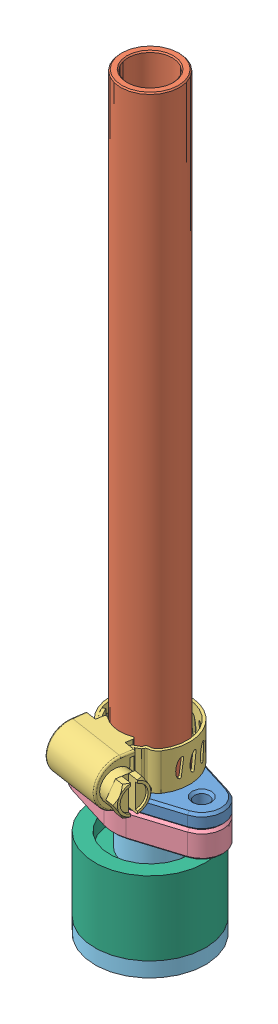
SolidWorks assembly AARL_QR_FR_TE, configuration Default. Lengths in mm.
Overall size (31.5 161.13 30.58).
6 component instances, 6 part files, 11 mates.
Components (placement in the parent):
- AARL_QR_FR_TE_001-1: AARL_QR_FR_TE_001 [Default] at origin size (31.5 15.88 15.88)
- AARL_QR_PN_PA_FL_SH_FL_001-1: AARL_QR_PN_PA_FL_SH_FL_001 [Resting] at (0 68.2625 0) size (12.7 130.18 12.7)
- AARL_Puppy_18_02_57_011-5388K140_Hose-Clamp-1: AARL_Puppy_18_02_57_011-5388K140_Hose-Clamp [5388K14] at (0 8.128 0) x (0.988722 0 0.149764) z (0 -1 0) size (19.43 23.71 9.91)
- AARL_QR_FR_TE_002-1: AARL_QR_FR_TE_002 [Default] x (1 0 0) z (0 -1 0) size (31.5 15.88 5.56)
- AARL_QR_FR_TE_003-1: AARL_QR_FR_TE_003 [Default] at (0 -27.7812 0) x (0.982152 0 0.18809) z (-0.18809 0 0.982152) size (23.81 22.23 23.81)
- AARL_QR_FR_TE_004-1: AARL_QR_FR_TE_004 [Default] at (0 -24.6062 0) x (-0.999983 0 0.005769) z (0 -1 0) size (23.81 23.81 15.88)
Mates (geometry in assembly coordinates):
- Concentric1: concentric anti-aligned: cylinder of AARL_QR_FR_TE_001-1 through (0 0 0) axis (0 -1 0) radius 4.3656; cylinder of AARL_QR_PN_PA_FL_SH_FL_001-1 through (0 79.8711 0) axis (0 1 0) radius 6.35
- Coincident1: coincident anti-aligned: plane of AARL_QR_FR_TE_001-1 through (7.9375 3.175 0) normal (0 1 0); plane of AARL_QR_PN_PA_FL_SH_FL_001-1 through (6.35 3.175 0) normal (0 -1 0)
- Concentric2: concentric aligned: cylinder of AARL_QR_PN_PA_FL_SH_FL_001-1 through (0 79.8711 0) axis (0 1 0) radius 6.35; cylinder of AARL_Puppy_18_02_57_011-5388K140_Hose-Clamp-1 through (0 3.175 0) axis (0 1 0) radius 6.5507
- Coincident2: coincident anti-aligned: plane of AARL_QR_FR_TE_001-1 through (7.9375 3.175 0) normal (0 1 0); plane of AARL_Puppy_18_02_57_011-5388K140_Hose-Clamp-1 through (0 3.175 0) normal (0 -1 0)
- Concentric6: concentric anti-aligned: cylinder of AARL_QR_FR_TE_001-1 through (-11.1125 23.3998 0) axis (0 -1 0) radius 1.5875; cylinder of AARL_QR_FR_TE_002-1 through (-11.1125 -5.5563 0) axis (0 1 0) radius 1.5875
- Concentric7: concentric anti-aligned: cylinder of AARL_QR_FR_TE_001-1 through (11.1125 23.3998 0) axis (0 -1 0) radius 1.5875; cylinder of AARL_QR_FR_TE_002-1 through (11.1125 -5.5563 0) axis (0 1 0) radius 1.5875
- Coincident5: coincident anti-aligned: plane of AARL_QR_FR_TE_001-1 through (0 0 0) normal (0 -1 0); plane of AARL_QR_FR_TE_002-1 through (-11.1125 0 0) normal (0 1 0)
- Concentric8: concentric aligned: cylinder of AARL_QR_FR_TE_002-1 through (0 -5.5563 0) axis (0 1 0) radius 1.5875; cylinder of AARL_QR_FR_TE_003-1 through (0 -21.4629 0) axis (0 1 0) radius 1.5875
- Coincident6: coincident anti-aligned: plane of AARL_QR_FR_TE_002-1 through (-11.1125 -5.5563 0) normal (0 -1 0); plane of AARL_QR_FR_TE_003-1 through (1.5592 -5.5563 0.2986) normal (0 1 0)
- Concentric9: concentric aligned: cylinder of AARL_QR_FR_TE_003-1 through (0 -21.4629 0) axis (0 1 0) radius 5.5563; cylinder of AARL_QR_FR_TE_004-1 through (0 -7.4193 0) axis (0 1 0) radius 5.5563
- Coincident8: coincident anti-aligned: plane of AARL_QR_FR_TE_003-1 through (5.4571 -24.6062 1.0451) normal (0 1 0); plane of AARL_QR_FR_TE_004-1 through (-5.5562 -24.6062 0.0321) normal (0 -1 0)
